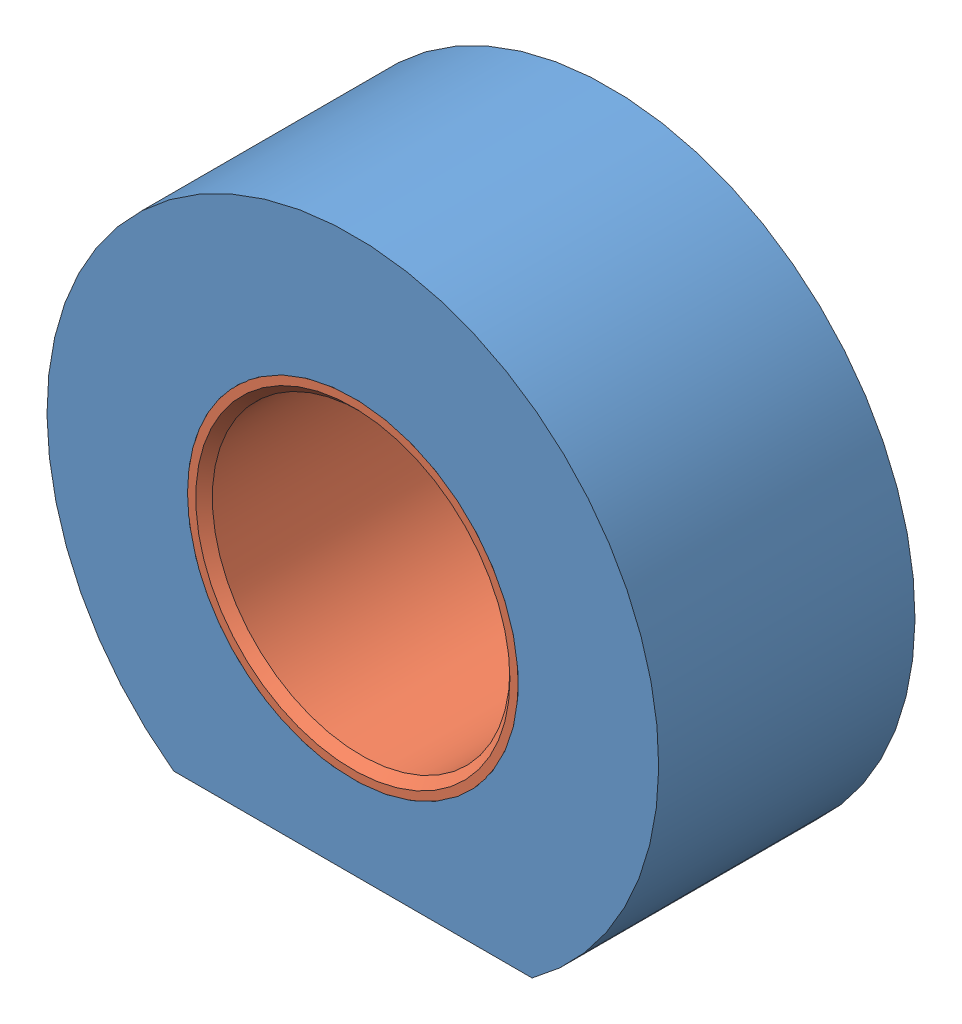
SolidWorks assembly Assembly Leg sleeve, configuration Default. Lengths in mm.
Overall size (37 33.49 15.5).
2 component instances, 2 part files, 2 mates.
Components (placement in the parent):
- 7. Leg Sleeve-1: 7. Leg Sleeve [Default] at (25.6177 19.3624 13.1921) size (37 33.49 15.5)
- 8. Sleeve-1: 8. Sleeve [Default] at (25.6177 19.3624 13.1921) size (20 20 15.5)
Mates (geometry in assembly coordinates):
- Concentric1: concentric: cylinder of 7. Leg Sleeve-1 through (25.6177 19.3624 28.6921) axis (0 0 -1) radius 10; cylinder of 8. Sleeve-1 through (25.6177 19.3624 28.6921) axis (0 0 -1) radius 10
- Coincident1: coincident aligned: plane of 7. Leg Sleeve-1 through (25.6177 19.3624 28.6921) normal (0 0 1); plane of 8. Sleeve-1 through (25.6177 19.3624 28.6921) normal (0 0 1)
